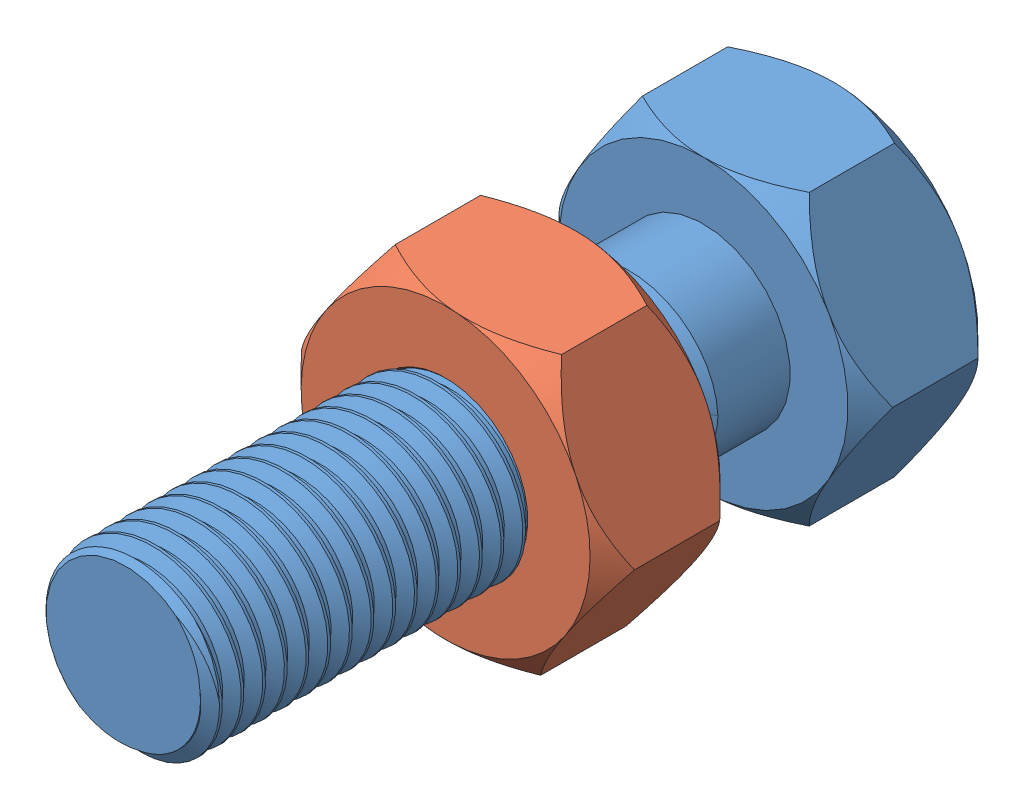
SolidWorks assembly Assem1, configuration Default. Lengths in mm.
Overall size (30.81 32.25 49.67).
2 component instances, 2 part files, 3 mates.
Components (placement in the parent):
- Part1-1: Part1 [Default] at (-16.1225 0.754 -12.342) size (25.4 20 49.67)
- Part2-1: Part2 [Default] at (-16.1225 0.754 5.5031) x (0.561357 0.827574 0) z (0 0 1) size (25.4 20 9)
Mates (geometry in assembly coordinates):
- Coincident2: coincident: line of assembly; line of assembly; axis of Part1-1 through (-16.1225 0.754 31.658) axis (0 0 -1); axis of Part2-1 through (-16.1225 0.754 35.6702) axis (0 0 -1)
- Screw1: screw = 1.5 mm: cylinder of assembly; line of assembly; cylinder of Part1-1 through (-16.1225 0.754 32.158) axis (0 0 -1) radius 6; axis of Part2-1 through (-16.1225 0.754 40.5031) axis (0 0 -1)
- LimitDistance1: limit distance = 8.845 mm: plane of Part2-1 through (-16.1225 0.754 1.0031) normal (0 0 -1); plane of Part1-1 through (-16.1225 0.754 -7.842) normal (0 0 1)
